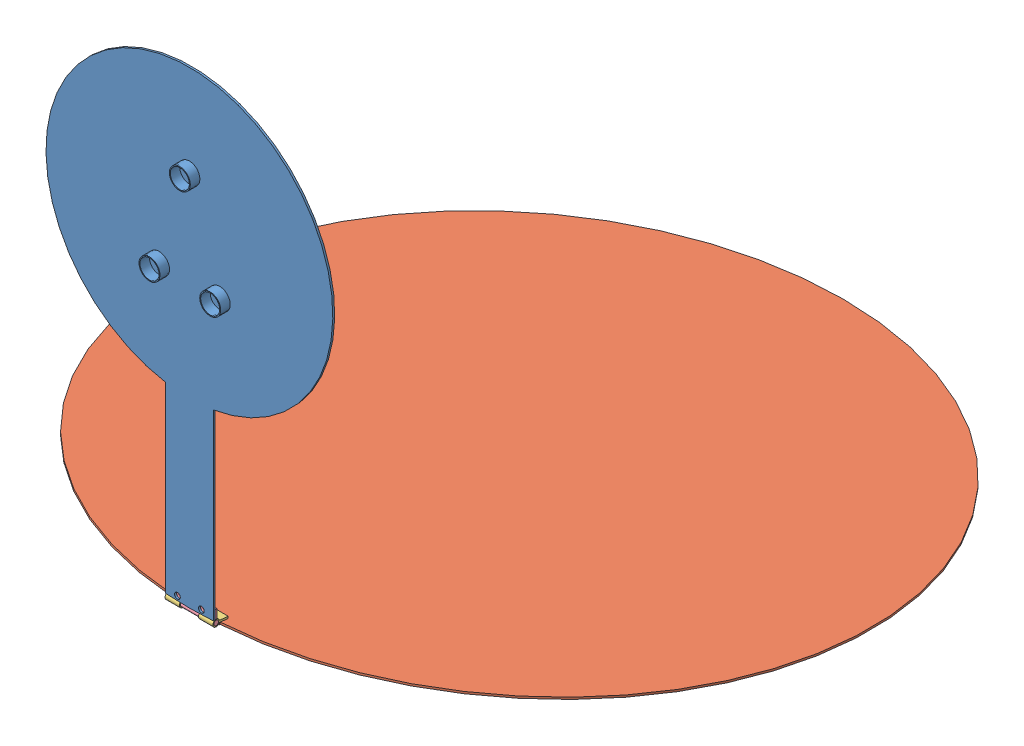
SolidWorks assembly CACHE ROUE COMPLET, configuration Défaut. Lengths in mm.
Overall size (680 554.04 693.9).
4 component instances, 4 part files, 6 mates.
Components (placement in the parent):
- interne-1: interne [Défaut] at (194.9658 -370.4238 484) size (300 490 12)
- externe-1: externe [Défaut] at (79.3445 -146.4972 -256.7801) x (1 0 0) z (0 -0.996322 0.085694) size (680 680 2)
- charniere 2-1: charniere 2 [Défaut] at (586.8432 -343.5534 -2571.2041) x (1 0 0) z (0 -0.996322 0.085694) size (50 16 7)
- charniere 1-1: charniere 1 [Défaut] at (-60.3378 72.6459 482) x (-1 0 0) z (0 0 1) size (50 15 5)
Mates (geometry in assembly coordinates):
- Coaxiale2: concentric aligned: cylinder of charniere 2-1 through (-8.8296 -81.865 483) axis (-1 0 0) radius 3.5; cylinder of charniere 1-1 through (26.1704 -81.865 483) axis (-1 0 0) radius 2.5
- Coïncidente5: coincident anti-aligned: circle of charniere 2-1; circle of charniere 1-1
- Coïncidente6: coincident aligned: circle of interne-1; circle of charniere 1-1
- Coïncidente7: coincident aligned: circle of interne-1; circle of charniere 1-1
- Coïncidente11: coincident anti-aligned: circle of externe-1; circle of charniere 2-1
- Coïncidente12: coincident anti-aligned: circle of externe-1; circle of charniere 2-1
